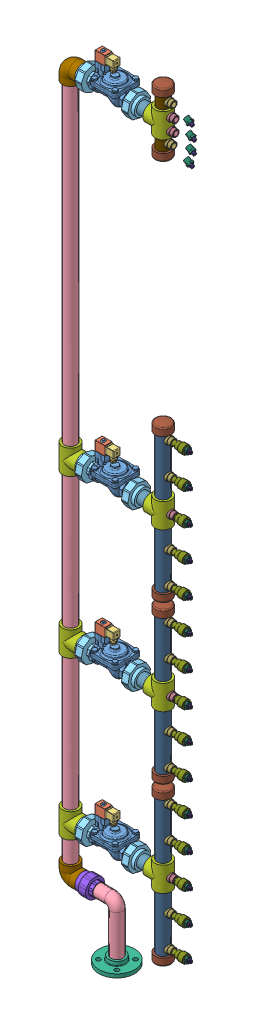
SolidWorks assembly PPR Water Splitter Assembly – Union Type, configuration Default. Lengths in mm.
Overall size (560.85 3301.11 212.13).
133 component instances, 19 part files, 17 mates.
Components (placement in the parent):
- solenoid_valve_sc_g238c020_3b_oh-1: solenoid_valve_sc_g238c020_3b_oh [Default] at (52.5 414 0) x (-1 0 0) z (0 0 -1) size (140 159.5 110)
  - solenoid_valve_1b_3b_oh-1: solenoid_valve_1b_3b_oh [Default] at origin size (140 159.5 110)
  - solenoid_valve_2b_3b_3b_oh-1: solenoid_valve_2b_3b_3b_oh [Default] at origin size (54 39 30)
  - solenoid_valve_3b_3b_3b_oh-1: solenoid_valve_3b_3b_3b_oh [Default] at (0 212 0) x (1 0 0) z (0 0 -1) size (37.4 51.76 29.51)
- DN40 Stainless-Steel Water Distributor Assembly-1: DN40 Stainless-Steel Water Distributor Assembly [Default] at origin size (334.07 3215.43 212.13)
  - DN50 PPR water distribution pipe-1: DN50 PPR water distribution pipe [Default] at origin size (244 3175 50)
  - DN50 PPR male-thread union-2: DN50 PPR male-thread union [Default] at (-110.1859 414 0) x (1 0 0) z (0 0.815822 -0.578303) size (73 95.5 95.5)
  - DN50 PPR male-thread union-3: DN50 PPR male-thread union [Default] at (-110.1859 1074 0) x (1 0 0) z (0 0.815822 -0.578303) size (73 95.5 95.5)
  - DN50 PPR male-thread union-4: DN50 PPR male-thread union [Default] at (-110.1859 1734 0) x (1 0 0) z (0 0.815822 -0.578303) size (73 95.5 95.5)
  - DN40-PN25 threaded flange-1: DN40-PN25 threaded flange [Default] at (0 -15 0) x (0 1 0) z (0.707107 0 0.707107) size (34 150 150)
  - DN50 PPR tee-1: DN50 PPR tee [Default] at (-194 414 0) size (85.5 103 68)
  - DN50 PPR female-thread straight connector-1: DN50 PPR female-thread straight connector [Default] at (-142.5 216 0) x (1 0 0) z (0 0.920901 -0.389797) size (67 79.98 79.98)
  - DN50 PPR elbow-1: DN50 PPR elbow [Default] at (-169 241 0) size (85.5 85.5 68)
  - DN50 PPR tee-2: DN50 PPR tee [Default] at (-194 1074 0) size (85.5 103 68)
  - DN50 PPR tee-3: DN50 PPR tee [Default] at (-194 1734 0) size (85.5 103 68)
  - DN50 PPR elbow-2: DN50 PPR elbow [Default] at (-169 3125 0) x (1 0 0) z (0 0 -1) size (85.5 85.5 68)
  - DN50 PPR male-thread union-5: DN50 PPR male-thread union [Default] at (-110.1859 3150 0) x (1 0 0) z (0 0.057891 0.998323) size (73 95.5 95.5)
- solenoid_valve_sc_g238c020_3b_oh-7: solenoid_valve_sc_g238c020_3b_oh [Default] at (52.5 1074 0) x (-1 0 0) z (0 0 -1) size (140 159.5 110)
  - solenoid_valve_1b_3b_oh-1: solenoid_valve_1b_3b_oh [Default] at origin size (140 159.5 110)
  - solenoid_valve_2b_3b_3b_oh-1: solenoid_valve_2b_3b_3b_oh [Default] at origin size (54 39 30)
  - solenoid_valve_3b_3b_3b_oh-1: solenoid_valve_3b_3b_3b_oh [Default] at (0 212 0) x (1 0 0) z (0 0 -1) size (37.4 51.76 29.51)
- solenoid_valve_sc_g238c020_3b_oh-8: solenoid_valve_sc_g238c020_3b_oh [Default] at (52.5 1734 0) x (-1 0 0) z (0 0 -1) size (140 159.5 110)
  - solenoid_valve_1b_3b_oh-1: solenoid_valve_1b_3b_oh [Default] at origin size (140 159.5 110)
  - solenoid_valve_2b_3b_3b_oh-1: solenoid_valve_2b_3b_3b_oh [Default] at origin size (54 39 30)
  - solenoid_valve_3b_3b_3b_oh-1: solenoid_valve_3b_3b_3b_oh [Default] at (0 212 0) x (1 0 0) z (0 0 -1) size (37.4 51.76 29.51)
- solenoid_valve_sc_g238c020_3b_oh-9: solenoid_valve_sc_g238c020_3b_oh [Default] at (52.5 3150 0) x (-1 0 0) z (0 0 -1) size (140 159.5 110)
  - solenoid_valve_1b_3b_oh-1: solenoid_valve_1b_3b_oh [Default] at origin size (140 159.5 110)
  - solenoid_valve_2b_3b_3b_oh-1: solenoid_valve_2b_3b_3b_oh [Default] at origin size (54 39 30)
  - solenoid_valve_3b_3b_3b_oh-1: solenoid_valve_3b_3b_3b_oh [Default] at (0 212 0) x (1 0 0) z (0 0 -1) size (37.4 51.76 29.51)
- DN50 PPR Distribution Pipe Assembly-1: DN50 PPR Distribution Pipe Assembly [Default] at (194 414 0) x (-1 0 0) z (0 0 -1) size (278.5 642.21 108.73)
  - DN50 PPR tee-1: DN50 PPR tee [Default] at origin size (85.5 103 68)
  - DN50 PPR distributor pipe-1: DN50 PPR distributor pipe [Default] at origin size (50 620 50)
  - DN50 PPR end cap-1: DN50 PPR end cap [Default] at (0 289.2744 0) x (0.993444 0 0.114321) z (-0.114321 0 0.993444) size (66.6 34.61 66.6)
  - DN50 PPR end cap-2: DN50 PPR end cap [Default] at (0 -289.2744 0) x (-0.999521 0 0.030939) z (0.030939 0 0.999521) size (66.6 34.61 66.6)
  - PPR weld in saddle 50–20-1: PPR weld in saddle 50–20 [Default] at (0 132 0) x (0 1 0) z (0 0 1) size (32 32.84 32)
  - PPR weld in saddle 75–20-1: PPR weld in saddle 75–20 [Default] at (3.5 0 0) x (0 1 0) z (0 0 1) size (32 33.38 32)
  - PPR weld in saddle 50–20-5: PPR weld in saddle 50–20 [Default] at (0 264 0) x (0 1 0) z (0 0 1) size (32 32.84 32)
  - DN50 PPR coupling–distributor joint-1: DN50 PPR coupling–distributor joint [Default] at (69 0 0) x (0 0.790854 -0.612005) z (0 0.612005 0.790854) size (50 82 50)
  - DN50 PPR male-thread union-1: DN50 PPR male-thread union [Default] at (118.8141 0 0) x (1 0 0) z (0 -0.1498 -0.988716) size (73 95.5 95.5)
  - PPR weld in saddle 50–20-6: PPR weld in saddle 50–20 [Default] at (0 -264 0) x (0 -1 0) z (0 0 -1) size (32 32.84 32)
  - PPR weld in saddle 50–20-7: PPR weld in saddle 50–20 [Default] at (0 -132 0) x (0 -1 0) z (0 0 -1) size (32 32.84 32)
  - Female Thread Reducer DN15-DN8-1: Female Thread Reducer DN15-DN8 [Default] at (-107.5 -264 0) size (23.99 26.56 23)
  - PPR Female threaded coupling 20xDN15-1: PPR Female threaded coupling 20xDN15 [Default] at (-60.5 -264 0) x (-1 0 0) z (0 -0.051033 -0.998697) size (53.5 35 35)
  - Spay MEG 1530-1: Spay MEG 1530 [Default] at (-98.5 -264 0) x (0 0 1) z (0 -1 0) size (13.5 20.5 15.59)
  - Female Thread Reducer DN15-DN8-2: Female Thread Reducer DN15-DN8 [Default] at (-107.5 -132 0) size (23.99 26.56 23)
  - Female Thread Reducer DN15-DN8-4: Female Thread Reducer DN15-DN8 [Default] at (-107.5 132 0) size (23.99 26.56 23)
  - Female Thread Reducer DN15-DN8-5: Female Thread Reducer DN15-DN8 [Default] at (-107.5 264 0) size (23.99 26.56 23)
  - Spay MEG 1530-2: Spay MEG 1530 [Default] at (-98.5 -132 0) x (0 0 1) z (0 -1 0) size (13.5 20.5 15.59)
  - Spay MEG 1530-4: Spay MEG 1530 [Default] at (-98.5 132 0) x (0 0 1) z (0 -1 0) size (13.5 20.5 15.59)
  - Spay MEG 1530-5: Spay MEG 1530 [Default] at (-98.5 264 0) x (0 0 1) z (0 -1 0) size (13.5 20.5 15.59)
  - PPR Female threaded coupling 20xDN15-2: PPR Female threaded coupling 20xDN15 [Default] at (-60.5 -132 0) x (-1 0 0) z (0 -0.051033 -0.998697) size (53.5 35 35)
  - PPR Female threaded coupling 20xDN15-4: PPR Female threaded coupling 20xDN15 [Default] at (-60.5 132 0) x (-1 0 0) z (0 -0.051033 -0.998697) size (53.5 35 35)
  - PPR Female threaded coupling 20xDN15-5: PPR Female threaded coupling 20xDN15 [Default] at (-60.5 264 0) x (-1 0 0) z (0 -0.051033 -0.998697) size (53.5 35 35)
  - PPR Female threaded coupling 20xDN15-6: PPR Female threaded coupling 20xDN15 [Default] at (-60.5 0 0) x (-1 0 0) z (0 0.107959 -0.994155) size (53.5 35 35)
  - Female Thread Reducer DN15-DN8-6: Female Thread Reducer DN15-DN8 [Default] at (-107.5 0 0) size (23.99 26.56 23)
  - Spay MEG 1530-9: Spay MEG 1530 [Default] at (-98.5 0 0) x (0 0 1) z (0 -1 0) size (13.5 20.5 15.59)
- DN50 PPR Distribution Pipe Assembly-2: DN50 PPR Distribution Pipe Assembly [Default] at (194 1074 0) x (-1 0 0) z (0 0 -1) size (278.5 642.21 108.73)
  - DN50 PPR tee-1: DN50 PPR tee [Default] at origin size (85.5 103 68)
  - DN50 PPR distributor pipe-1: DN50 PPR distributor pipe [Default] at origin size (50 620 50)
  - DN50 PPR end cap-1: DN50 PPR end cap [Default] at (0 289.2744 0) x (0.993444 0 0.114321) z (-0.114321 0 0.993444) size (66.6 34.61 66.6)
  - DN50 PPR end cap-2: DN50 PPR end cap [Default] at (0 -289.2744 0) x (-0.999521 0 0.030939) z (0.030939 0 0.999521) size (66.6 34.61 66.6)
  - PPR weld in saddle 50–20-1: PPR weld in saddle 50–20 [Default] at (0 132 0) x (0 1 0) z (0 0 1) size (32 32.84 32)
  - PPR weld in saddle 75–20-1: PPR weld in saddle 75–20 [Default] at (3.5 0 0) x (0 1 0) z (0 0 1) size (32 33.38 32)
  - PPR weld in saddle 50–20-5: PPR weld in saddle 50–20 [Default] at (0 264 0) x (0 1 0) z (0 0 1) size (32 32.84 32)
  - DN50 PPR coupling–distributor joint-1: DN50 PPR coupling–distributor joint [Default] at (69 0 0) x (0 0.790854 -0.612005) z (0 0.612005 0.790854) size (50 82 50)
  - DN50 PPR male-thread union-1: DN50 PPR male-thread union [Default] at (118.8141 0 0) x (1 0 0) z (0 -0.1498 -0.988716) size (73 95.5 95.5)
  - PPR weld in saddle 50–20-6: PPR weld in saddle 50–20 [Default] at (0 -264 0) x (0 -1 0) z (0 0 -1) size (32 32.84 32)
  - PPR weld in saddle 50–20-7: PPR weld in saddle 50–20 [Default] at (0 -132 0) x (0 -1 0) z (0 0 -1) size (32 32.84 32)
  - Female Thread Reducer DN15-DN8-1: Female Thread Reducer DN15-DN8 [Default] at (-107.5 -264 0) size (23.99 26.56 23)
  - PPR Female threaded coupling 20xDN15-1: PPR Female threaded coupling 20xDN15 [Default] at (-60.5 -264 0) x (-1 0 0) z (0 -0.051033 -0.998697) size (53.5 35 35)
  - Spay MEG 1530-1: Spay MEG 1530 [Default] at (-98.5 -264 0) x (0 0 1) z (0 -1 0) size (13.5 20.5 15.59)
  - Female Thread Reducer DN15-DN8-2: Female Thread Reducer DN15-DN8 [Default] at (-107.5 -132 0) size (23.99 26.56 23)
  - Female Thread Reducer DN15-DN8-4: Female Thread Reducer DN15-DN8 [Default] at (-107.5 132 0) size (23.99 26.56 23)
  - Female Thread Reducer DN15-DN8-5: Female Thread Reducer DN15-DN8 [Default] at (-107.5 264 0) size (23.99 26.56 23)
  - Spay MEG 1530-2: Spay MEG 1530 [Default] at (-98.5 -132 0) x (0 0 1) z (0 -1 0) size (13.5 20.5 15.59)
  - Spay MEG 1530-4: Spay MEG 1530 [Default] at (-98.5 132 0) x (0 0 1) z (0 -1 0) size (13.5 20.5 15.59)
  - Spay MEG 1530-5: Spay MEG 1530 [Default] at (-98.5 264 0) x (0 0 1) z (0 -1 0) size (13.5 20.5 15.59)
  - PPR Female threaded coupling 20xDN15-2: PPR Female threaded coupling 20xDN15 [Default] at (-60.5 -132 0) x (-1 0 0) z (0 -0.051033 -0.998697) size (53.5 35 35)
  - PPR Female threaded coupling 20xDN15-4: PPR Female threaded coupling 20xDN15 [Default] at (-60.5 132 0) x (-1 0 0) z (0 -0.051033 -0.998697) size (53.5 35 35)
  - PPR Female threaded coupling 20xDN15-5: PPR Female threaded coupling 20xDN15 [Default] at (-60.5 264 0) x (-1 0 0) z (0 -0.051033 -0.998697) size (53.5 35 35)
  - PPR Female threaded coupling 20xDN15-6: PPR Female threaded coupling 20xDN15 [Default] at (-60.5 0 0) x (-1 0 0) z (0 0.107959 -0.994155) size (53.5 35 35)
  - Female Thread Reducer DN15-DN8-6: Female Thread Reducer DN15-DN8 [Default] at (-107.5 0 0) size (23.99 26.56 23)
  - Spay MEG 1530-9: Spay MEG 1530 [Default] at (-98.5 0 0) x (0 0 1) z (0 -1 0) size (13.5 20.5 15.59)
- DN50 PPR Distribution Pipe Assembly-3: DN50 PPR Distribution Pipe Assembly [Default] at (194 1734 0) x (-1 0 0) z (0 0 -1) size (278.5 642.21 108.73)
  - DN50 PPR tee-1: DN50 PPR tee [Default] at origin size (85.5 103 68)
  - DN50 PPR distributor pipe-1: DN50 PPR distributor pipe [Default] at origin size (50 620 50)
  - DN50 PPR end cap-1: DN50 PPR end cap [Default] at (0 289.2744 0) x (0.993444 0 0.114321) z (-0.114321 0 0.993444) size (66.6 34.61 66.6)
  - DN50 PPR end cap-2: DN50 PPR end cap [Default] at (0 -289.2744 0) x (-0.999521 0 0.030939) z (0.030939 0 0.999521) size (66.6 34.61 66.6)
  - PPR weld in saddle 50–20-1: PPR weld in saddle 50–20 [Default] at (0 132 0) x (0 1 0) z (0 0 1) size (32 32.84 32)
  - PPR weld in saddle 75–20-1: PPR weld in saddle 75–20 [Default] at (3.5 0 0) x (0 1 0) z (0 0 1) size (32 33.38 32)
  - PPR weld in saddle 50–20-5: PPR weld in saddle 50–20 [Default] at (0 264 0) x (0 1 0) z (0 0 1) size (32 32.84 32)
  - DN50 PPR coupling–distributor joint-1: DN50 PPR coupling–distributor joint [Default] at (69 0 0) x (0 0.790854 -0.612005) z (0 0.612005 0.790854) size (50 82 50)
  - DN50 PPR male-thread union-1: DN50 PPR male-thread union [Default] at (118.8141 0 0) x (1 0 0) z (0 -0.1498 -0.988716) size (73 95.5 95.5)
  - PPR weld in saddle 50–20-6: PPR weld in saddle 50–20 [Default] at (0 -264 0) x (0 -1 0) z (0 0 -1) size (32 32.84 32)
  - PPR weld in saddle 50–20-7: PPR weld in saddle 50–20 [Default] at (0 -132 0) x (0 -1 0) z (0 0 -1) size (32 32.84 32)
  - Female Thread Reducer DN15-DN8-1: Female Thread Reducer DN15-DN8 [Default] at (-107.5 -264 0) size (23.99 26.56 23)
  - PPR Female threaded coupling 20xDN15-1: PPR Female threaded coupling 20xDN15 [Default] at (-60.5 -264 0) x (-1 0 0) z (0 -0.051033 -0.998697) size (53.5 35 35)
  - Spay MEG 1530-1: Spay MEG 1530 [Default] at (-98.5 -264 0) x (0 0 1) z (0 -1 0) size (13.5 20.5 15.59)
  - Female Thread Reducer DN15-DN8-2: Female Thread Reducer DN15-DN8 [Default] at (-107.5 -132 0) size (23.99 26.56 23)
  - Female Thread Reducer DN15-DN8-4: Female Thread Reducer DN15-DN8 [Default] at (-107.5 132 0) size (23.99 26.56 23)
  - Female Thread Reducer DN15-DN8-5: Female Thread Reducer DN15-DN8 [Default] at (-107.5 264 0) size (23.99 26.56 23)
  - Spay MEG 1530-2: Spay MEG 1530 [Default] at (-98.5 -132 0) x (0 0 1) z (0 -1 0) size (13.5 20.5 15.59)
  - Spay MEG 1530-4: Spay MEG 1530 [Default] at (-98.5 132 0) x (0 0 1) z (0 -1 0) size (13.5 20.5 15.59)
  - Spay MEG 1530-5: Spay MEG 1530 [Default] at (-98.5 264 0) x (0 0 1) z (0 -1 0) size (13.5 20.5 15.59)
  - PPR Female threaded coupling 20xDN15-2: PPR Female threaded coupling 20xDN15 [Default] at (-60.5 -132 0) x (-1 0 0) z (0 -0.051033 -0.998697) size (53.5 35 35)
  - PPR Female threaded coupling 20xDN15-4: PPR Female threaded coupling 20xDN15 [Default] at (-60.5 132 0) x (-1 0 0) z (0 -0.051033 -0.998697) size (53.5 35 35)
  - PPR Female threaded coupling 20xDN15-5: PPR Female threaded coupling 20xDN15 [Default] at (-60.5 264 0) x (-1 0 0) z (0 -0.051033 -0.998697) size (53.5 35 35)
  - PPR Female threaded coupling 20xDN15-6: PPR Female threaded coupling 20xDN15 [Default] at (-60.5 0 0) x (-1 0 0) z (0 0.107959 -0.994155) size (53.5 35 35)
  - Female Thread Reducer DN15-DN8-6: Female Thread Reducer DN15-DN8 [Default] at (-107.5 0 0) size (23.99 26.56 23)
  - Spay MEG 1530-9: Spay MEG 1530 [Default] at (-98.5 0 0) x (0 0 1) z (0 -1 0) size (13.5 20.5 15.59)
- DN50 PPR Distribution Pipe Assembly – Upper-1: DN50 PPR Distribution Pipe Assembly – Upper [Default] at (194 3150 0) x (-1 0 0) z (0 0 -1) size (298.35 272.21 108.73)
  - DN50 PPR tee-1: DN50 PPR tee [Default] at origin size (85.5 103 68)
  - upper DN50 PPR distributor-1: upper DN50 PPR distributor [Default] at origin size (50 250 50)
  - DN50 PPR end cap-1: DN50 PPR end cap [Default] at (0 104.2744 0) x (0.993444 0 0.114321) z (-0.114321 0 0.993444) size (66.6 34.61 66.6)
  - DN50 PPR end cap-2: DN50 PPR end cap [Default] at (0 -104.2744 0) x (-0.999521 0 0.030939) z (0.030939 0 0.999521) size (66.6 34.61 66.6)
  - PPR weld in saddle 50–20-1: PPR weld in saddle 50–20 [Default] at (0 75 0) x (0 1 0) z (0 0 1) size (32 32.84 32)
  - DN50 PPR coupling–distributor joint-1: DN50 PPR coupling–distributor joint [Default] at (69 0 0) x (0 0.790854 -0.612005) z (0 0.612005 0.790854) size (50 82 50)
  - DN50 PPR male-thread union-1: DN50 PPR male-thread union [Default] at (118.8141 0 0) x (1 0 0) z (0 -0.1498 -0.988716) size (73 95.5 95.5)
  - PPR weld in saddle 75–20-2: PPR weld in saddle 75–20 [Default] at (3.5 25 0) x (0 1 0) z (0 0 1) size (32 33.38 32)
  - PPR weld in saddle 50–20-8: PPR weld in saddle 50–20 [Default] at (0 -75 0) x (0 -1 0) z (0 0 -1) size (32 32.84 32)
  - PPR weld in saddle 75–20-3: PPR weld in saddle 75–20 [Default] at (3.5 -25 0) x (0 -1 0) z (0 0 -1) size (32 33.38 32)
  - PPR Female threaded coupling 20xDN15 45deg-1: PPR Female threaded coupling 20xDN15 45deg [Default] at (-74.4234 67.25 0) x (-0.866025 -0.5 0) z (0 0 -1) size (84.48 41.16 35)
  - Female Thread Reducer DN15-DN8-1: Female Thread Reducer DN15-DN8 [Default] at (-115.9926 43.25 0) x (0.866025 0.5 0) z (0 0 1) size (23.99 26.56 23)
  - Spay MEG 1530-1: Spay MEG 1530 [Default] at (-108.1984 47.75 0) x (0 0 -1) z (-0.5 0.866025 0) size (13.5 20.5 15.59)
  - PPR Female threaded coupling 20xDN15 45deg-3: PPR Female threaded coupling 20xDN15 45deg [Default] at (-83.4234 17.25 0) x (-0.866025 -0.5 0) z (0 0 -1) size (84.48 41.16 35)
  - Female Thread Reducer DN15-DN8-2: Female Thread Reducer DN15-DN8 [Default] at (-124.9926 -6.75 0) x (0.866025 0.5 0) z (0.112965 -0.195661 0.974143) size (23.99 26.56 23)
  - Spay MEG 1530-2: Spay MEG 1530 [Default] at (-117.1984 -2.25 0) x (0 0 -1) z (-0.5 0.866025 0) size (13.5 20.5 15.59)
  - PPR Female threaded coupling 20xDN15 45deg-4: PPR Female threaded coupling 20xDN15 45deg [Default] at (-83.4234 -32.75 0) x (-0.866025 -0.5 0) z (0 0 -1) size (84.48 41.16 35)
  - Female Thread Reducer DN15-DN8-3: Female Thread Reducer DN15-DN8 [Default] at (-124.9926 -56.75 0) x (0.866025 0.5 0) z (0.225773 -0.391051 0.892247) size (23.99 26.56 23)
  - Spay MEG 1530-3: Spay MEG 1530 [Default] at (-117.1984 -52.25 0) x (0 0 -1) z (-0.5 0.866025 0) size (13.5 20.5 15.59)
  - PPR Female threaded coupling 20xDN15 45deg-5: PPR Female threaded coupling 20xDN15 45deg [Default] at (-74.4234 -82.75 0) x (-0.866025 -0.5 0) z (0 0 -1) size (84.48 41.16 35)
  - Female Thread Reducer DN15-DN8-4: Female Thread Reducer DN15-DN8 [Default] at (-115.9926 -106.75 0) x (0.866025 0.5 0) z (0.316742 -0.548613 0.773756) size (23.99 26.56 23)
  - Spay MEG 1530-4: Spay MEG 1530 [Default] at (-108.1984 -102.25 0) x (0 0 -1) z (-0.5 0.866025 0) size (13.5 20.5 15.59)
Mates (geometry in assembly coordinates):
- Coincident26: coincident anti-aligned: line of rap ong inox chia nuoc DN40-1 through (190 0 190) axis (0 0 -1)
- Coincident28: coincident aligned: plane of rap ong inox chia nuoc DN40-1 through (0 0 0) normal (0 0 1); plane of assembly through (0 0 0) normal (0 0 1)
- Coincident29: coincident aligned: plane of rap ong inox chia nuoc DN40-1 through (0 0 0) normal (0 1 0); plane of assembly through (0 0 0) normal (0 1 0)
- Coincident31: coincident anti-aligned: plane of solenoid_valve_sc_g238c020_3b-1 through (52.5 414 0) normal (0 0 -1); plane of rap ong inox chia nuoc DN40-1 through (0 0 0) normal (0 0 1)
- Concentric17: concentric: cylinder of assembly through (-72.45 3150 0) axis (1 0 0) radius 21.8166; cone of ? through (-87.5 3150 0) axis (-1 0 0)
- Coincident36: coincident: plane of ? through (-72.45 3126.1555 -3.829) normal (1 0 0); plane of ? through (-87.5 3150 0) normal (-1 0 0)
- Coincident37: coincident anti-aligned: plane of rap ong inox chia nuoc DN40-1 through (0 0 0) normal (0 0 1); plane of solenoid_valve_sc_g238c020_3b-9 through (52.5 3150 0) normal (0 0 -1)
- Concentric19: concentric anti-aligned: cylinder of solenoid_valve_sc_g238c020_3b-1/solenoid_valve_1b_3b-1 through (-87.5 414 0) axis (-1 0 0) radius 22.4225; cylinder of rap ong inox chia nuoc DN40-1/Zac co ren ngoai DN50 PPR-2 through (-87.5 414 0) axis (1 0 0) radius 21.8166
- Coincident40: coincident anti-aligned: plane of solenoid_valve_sc_g238c020_3b-1/solenoid_valve_1b_3b-1 through (-87.5 414 0) normal (-1 0 0); plane of rap ong inox chia nuoc DN40-1/Zac co ren ngoai DN50 PPR-2 through (-87.5 434.0905 28.342) normal (1 0 0)
- Coincident42: coincident anti-aligned: plane of DN50 PPR Distribution Pipe Assembly-1 through (194 414 0) normal (0 0 -1); plane of assembly through (0 0 0) normal (0 0 1)
- Concentric24: concentric anti-aligned: cylinder of solenoid_valve_sc_g238c020_3b-1/solenoid_valve_1b_3b-1 through (52.5 414 0) axis (1 0 0) radius 22.4225; cylinder of rap ong chia DN50 PPR-1/Zac co ren ngoai DN50 PPR-1 through (52.5 414 0) axis (-1 0 0) radius 21.8166
- Coincident47: coincident anti-aligned: plane of solenoid_valve_sc_g238c020_3b-1/solenoid_valve_1b_3b-1 through (52.5 414 0) normal (1 0 0); plane of rap ong chia DN50 PPR-1/Zac co ren ngoai DN50 PPR-1 through (52.5 448.3485 5.2041) normal (-1 0 0)
- Concentric25: concentric anti-aligned: cylinder of solenoid_valve_sc_g238c020_3b-9/solenoid_valve_1b_3b-1 through (52.5 3150 0) axis (1 0 0) radius 22.4225; cylinder of rap ong chia DN50 PPR - tren-1/Zac co ren ngoai DN50 PPR-1 through (52.5 3150 0) axis (-1 0 0) radius 21.8166
- Coincident48: coincident anti-aligned: plane of solenoid_valve_sc_g238c020_3b-9/solenoid_valve_1b_3b-1 through (52.5 3150 0) normal (1 0 0); plane of rap ong chia DN50 PPR - tren-1/Zac co ren ngoai DN50 PPR-1 through (52.5 3184.3485 5.2041) normal (-1 0 0)
- Coincident49: coincident anti-aligned: plane of DN50 PPR Distribution Pipe Assembly – Upper-1 through (194 3150 0) normal (0 0 -1); plane of assembly through (0 0 0) normal (0 0 1)
- Concentric26: concentric anti-aligned: cylinder of rap ong inox chia nuoc DN40-1/Zac co ren ngoai DN50 PPR-5 through (-87.5 3150 0) axis (1 0 0) radius 21.8166; cylinder of solenoid_valve_sc_g238c020_3b-9/solenoid_valve_1b_3b-1 through (-87.5 3150 0) axis (-1 0 0) radius 22.4225
- Coincident50: coincident anti-aligned: plane of rap ong inox chia nuoc DN40-1/Zac co ren ngoai DN50 PPR-5 through (-87.5 3115.3178 2.0112) normal (1 0 0); plane of solenoid_valve_sc_g238c020_3b-9/solenoid_valve_1b_3b-1 through (-87.5 3150 0) normal (-1 0 0)
